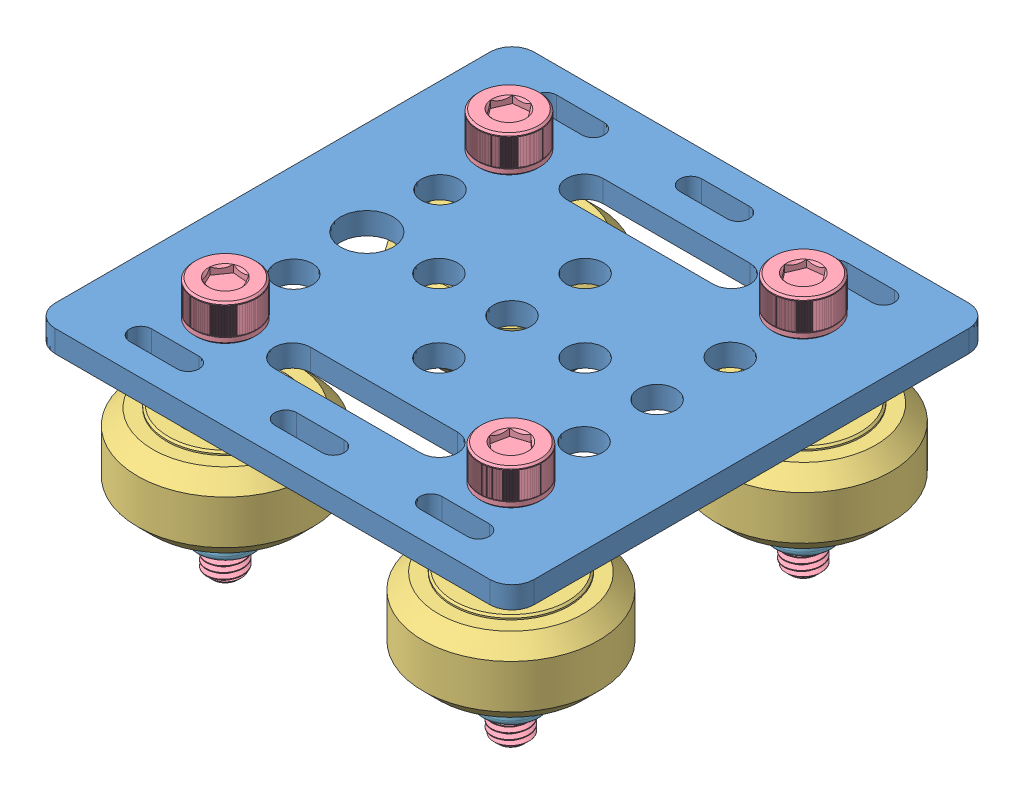
SolidWorks assembly Single Gantry Platform, configuration Default. Lengths in mm.
Overall size (72.95 35 73.59).
21 component instances, 7 part files, 40 mates.
Components (placement in the parent):
- Single Gantry Platform-1: Single Gantry Platform [Default] at (20.9715 37.2499 49.0083) size (65.5 3 65.5)
- Asymmetric_bushing-1: Asymmetric_bushing [Default] at (1.1215 35.4999 69.0083) x (0 -1 0) z (-0.085462 0 0.996341) size (8.5 10 10)
- V_slot_wheel-1: V_slot_wheel [Default] at (1.819 24.6999 69.0682) x (0 1 0) z (0.754284 0 0.656549) size (11.1 24 24)
- MT_M5_bolt-1: MT_M5_bolt [30mm] at (1.819 27.7499 69.0682) x (-0.996341 0 -0.085462) z (0 1 0) size (8.5 8.5 35)
- MT_M5_nut-1: MT_M5_nut [Default] at (1.819 16.6999 69.0682) x (0 -1 0) z (-0.615676 0 0.787999) size (5 9.24 8)
- MT_M5_Washer-1: MT_M5_Washer [Default] at (1.819 30.7499 69.0682) x (0 -1 0) z (0 0 1) size (1 8 8)
- Asymmetric_bushing-2: Asymmetric_bushing [Default] at (1.1215 35.4999 29.0083) x (0 -1 0) z (-0.985048 0 0.172282) size (8.5 10 10)
- V_slot_wheel-2: V_slot_wheel [Default] at (1.2421 24.6999 29.6979) x (0 1 0) z (0.864498 0 0.502636) size (11.1 24 24)
- MT_M5_bolt-2: MT_M5_bolt [30mm] at (1.2421 27.7499 29.6979) x (0.398878 0 -0.917004) z (0 1 0) size (8.5 8.5 35)
- MT_M5_nut-2: MT_M5_nut [Default] at (1.2421 16.6999 29.6979) x (0 -1 0) z (-0.456142 0 0.889907) size (5 9.24 8)
- MT_M5_Washer-2: MT_M5_Washer [Default] at (1.2421 30.7499 29.6979) x (0 -1 0) z (0.188455 0 0.982082) size (1 8 8)
- V_slot_wheel-4: V_slot_wheel [Default] at (40.8215 24.6999 29.0083) x (0 1 0) z (-0.83873 0 0.544547) size (11.1 24 24)
- MT_M5_bolt-4: MT_M5_bolt [30mm] at (40.8215 27.7499 29.0083) x (0.606014 0 0.795454) z (0 1 0) size (8.5 8.5 35)
- MT_M5_nut-4: MT_M5_nut [Default] at (40.8215 16.6999 29.0083) x (0 -1 0) z (-0.889907 0 -0.456142) size (5 9.24 8)
- MT_M5_Washer-4: MT_M5_Washer [Default] at (40.8215 30.7499 29.0083) x (0 -1 0) z (-0.982082 0 0.188455) size (1 8 8)
- Symmetric_bushing-1: Symmetric_bushing [Default] at (40.8215 34.2499 29.0083) x (0 -1 0) z (0 0 1) size (6 10 10)
- V_slot_wheel-6: V_slot_wheel [Default] at (40.8215 24.6999 69.0083) x (0 1 0) z (-0.721079 0 0.692853) size (11.1 24 24)
- MT_M5_bolt-6: MT_M5_bolt [30mm] at (40.8215 27.7499 69.0083) x (0.745063 0 0.666994) z (0 1 0) size (8.5 8.5 35)
- MT_M5_nut-6: MT_M5_nut [Default] at (40.8215 16.6999 69.0083) x (0 -1 0) z (-0.959924 0 -0.280262) size (5 9.24 8)
- MT_M5_Washer-6: MT_M5_Washer [Default] at (40.8215 30.7499 69.0083) x (0 -1 0) z (-0.92897 0 0.370156) size (1 8 8)
- Symmetric_bushing-2: Symmetric_bushing [Default] at (40.8215 34.2499 69.0083) x (0 -1 0) z (0.188455 0 0.982082) size (6 10 10)
Mates (geometry in assembly coordinates):
- Concentric1: concentric aligned: cylinder of Single Gantry Platform-1 through (1.1215 37.2499 69.0083) axis (0 1 0) radius 3.6; cylinder of Asymmetric_bushing-1 through (1.1215 35.4999 69.0083) axis (0 1 0) radius 3.55
- Concentric2: concentric aligned: cylinder of Asymmetric_bushing-1 through (1.819 39.7499 69.0682) axis (0 -1 0) radius 2.5; cylinder of MT_M5_bolt-1 through (1.819 10.2499 69.0682) axis (0 -1 0) radius 4.25
- Coincident2: coincident anti-aligned: plane of Single Gantry Platform-1 through (20.9715 37.2499 49.0083) normal (0 -1 0); plane of Asymmetric_bushing-1 through (6.1032 37.2499 69.4356) normal (0 1 0)
- Coincident3: coincident anti-aligned: plane of Single Gantry Platform-1 through (20.9715 40.2499 49.0083) normal (0 1 0); plane of MT_M5_bolt-1 through (1.4771 40.2499 73.0535) normal (0 -1 0)
- Coincident4: coincident anti-aligned: plane of Asymmetric_bushing-1 through (1.1215 31.2499 69.0083) normal (0 -1 0); plane of MT_M5_Washer-1 through (1.819 31.2499 69.0682) normal (0 1 0)
- Concentric3: concentric anti-aligned: cylinder of MT_M5_bolt-1 through (1.819 10.2499 69.0682) axis (0 -1 0) radius 4.25; cylinder of MT_M5_Washer-1 through (1.819 30.2499 69.0682) axis (0 1 0) radius 2.6
- Concentric4: concentric anti-aligned: cylinder of V_slot_wheel-1 through (1.819 24.1499 69.0682) axis (0 1 0) radius 2.5; cylinder of MT_M5_bolt-1 through (1.819 10.2499 69.0682) axis (0 -1 0) radius 4.25
- Coincident5: coincident anti-aligned: plane of V_slot_wheel-1 through (-1.3105 30.2499 72.6634) normal (0 1 0); plane of MT_M5_Washer-1 through (1.819 30.2499 69.0682) normal (0 -1 0)
- Concentric5: concentric aligned: cylinder of MT_M5_bolt-1 through (1.819 10.2499 69.0682) axis (0 -1 0) radius 4.25; cylinder of MT_M5_nut-1 through (1.819 19.1499 69.0682) axis (0 -1 0) radius 2.1
- Coincident6: coincident anti-aligned: plane of V_slot_wheel-1 through (0.0135 19.1499 71.1424) normal (0 -1 0); plane of MT_M5_nut-1 through (-3.1064 19.1499 75.3721) normal (0 1 0)
- Concentric6: concentric aligned: cylinder of Asymmetric_bushing-2 through (1.2421 39.7499 29.6979) axis (0 -1 0) radius 2.5; cylinder of MT_M5_bolt-2 through (1.2421 10.2499 29.6979) axis (0 -1 0) radius 4.25
- Coincident7: coincident anti-aligned: plane of Asymmetric_bushing-2 through (1.1215 31.2499 29.0083) normal (0 -1 0); plane of MT_M5_Washer-2 through (1.2421 31.2499 29.6979) normal (0 1 0)
- Concentric7: concentric anti-aligned: cylinder of MT_M5_bolt-2 through (1.2421 10.2499 29.6979) axis (0 -1 0) radius 4.25; cylinder of MT_M5_Washer-2 through (1.2421 30.2499 29.6979) axis (0 1 0) radius 2.6
- Concentric8: concentric anti-aligned: cylinder of V_slot_wheel-2 through (1.2421 24.1499 29.6979) axis (0 1 0) radius 2.5; cylinder of MT_M5_bolt-2 through (1.2421 10.2499 29.6979) axis (0 -1 0) radius 4.25
- Coincident8: coincident anti-aligned: plane of V_slot_wheel-2 through (-1.1537 30.2499 33.8185) normal (0 1 0); plane of MT_M5_Washer-2 through (1.2421 30.2499 29.6979) normal (0 -1 0)
- Concentric9: concentric aligned: cylinder of MT_M5_bolt-2 through (1.2421 10.2499 29.6979) axis (0 -1 0) radius 4.25; cylinder of MT_M5_nut-2 through (1.2421 19.1499 29.6979) axis (0 -1 0) radius 2.1
- Coincident9: coincident anti-aligned: plane of V_slot_wheel-2 through (-0.1401 19.1499 32.0752) normal (0 -1 0); plane of MT_M5_nut-2 through (-2.407 19.1499 36.8171) normal (0 1 0)
- Concentric10: concentric aligned: cylinder of Single Gantry Platform-1 through (1.1215 37.2499 29.0083) axis (0 1 0) radius 3.6; cylinder of Asymmetric_bushing-2 through (1.1215 35.4999 29.0083) axis (0 1 0) radius 3.55
- Coincident10: coincident anti-aligned: plane of Single Gantry Platform-1 through (20.9715 37.2499 49.0083) normal (0 -1 0); plane of Asymmetric_bushing-2 through (1.9829 37.2499 33.9336) normal (0 1 0)
- Coincident11: coincident anti-aligned: plane of Single Gantry Platform-1 through (20.9715 40.2499 49.0083) normal (0 1 0); plane of MT_M5_bolt-2 through (-2.4259 40.2499 28.1024) normal (0 -1 0)
- Concentric17: concentric anti-aligned: cylinder of MT_M5_bolt-4 through (40.8215 10.2499 29.0083) axis (0 -1 0) radius 4.25; cylinder of MT_M5_Washer-4 through (40.8215 30.2499 29.0083) axis (0 1 0) radius 2.6
- Concentric18: concentric anti-aligned: cylinder of V_slot_wheel-4 through (40.8215 24.1499 29.0083) axis (0 1 0) radius 2.5; cylinder of MT_M5_bolt-4 through (40.8215 10.2499 29.0083) axis (0 -1 0) radius 4.25
- Coincident18: coincident anti-aligned: plane of V_slot_wheel-4 through (38.226 30.2499 25.0105) normal (0 1 0); plane of MT_M5_Washer-4 through (40.8215 30.2499 29.0083) normal (0 -1 0)
- Concentric19: concentric aligned: cylinder of MT_M5_bolt-4 through (40.8215 10.2499 29.0083) axis (0 -1 0) radius 4.25; cylinder of MT_M5_nut-4 through (40.8215 19.1499 29.0083) axis (0 -1 0) radius 2.1
- Coincident19: coincident anti-aligned: plane of V_slot_wheel-4 through (39.324 19.1499 26.7018) normal (0 -1 0); plane of MT_M5_nut-4 through (33.7023 19.1499 25.3592) normal (0 1 0)
- Coincident21: coincident anti-aligned: plane of Single Gantry Platform-1 through (20.9715 40.2499 49.0083) normal (0 1 0); plane of MT_M5_bolt-4 through (44.0033 40.2499 26.5843) normal (0 -1 0)
- Concentric25: concentric anti-aligned: cylinder of Symmetric_bushing-1 through (40.8215 31.2499 29.0083) axis (0 1 0) radius 2.55; cylinder of MT_M5_bolt-4 through (40.8215 10.2499 29.0083) axis (0 -1 0) radius 4.25
- Coincident27: coincident anti-aligned: plane of Single Gantry Platform-1 through (20.9715 37.2499 49.0083) normal (0 -1 0); plane of Symmetric_bushing-1 through (40.8215 37.2499 29.0083) normal (0 1 0)
- Coincident28: coincident anti-aligned: plane of Symmetric_bushing-1 through (40.8215 31.2499 29.0083) normal (0 -1 0); plane of MT_M5_Washer-4 through (40.8215 31.2499 29.0083) normal (0 1 0)
- Concentric26: concentric aligned: cylinder of Single Gantry Platform-1 through (40.8215 40.2499 29.0083) axis (0 -1 0) radius 2.55; cylinder of MT_M5_bolt-4 through (40.8215 10.2499 29.0083) axis (0 -1 0) radius 4.25
- Concentric27: concentric anti-aligned: cylinder of MT_M5_bolt-6 through (40.8215 10.2499 69.0083) axis (0 -1 0) radius 4.25; cylinder of MT_M5_Washer-6 through (40.8215 30.2499 69.0083) axis (0 1 0) radius 2.6
- Concentric28: concentric anti-aligned: cylinder of V_slot_wheel-6 through (40.8215 24.1499 69.0083) axis (0 1 0) radius 2.5; cylinder of MT_M5_bolt-6 through (40.8215 10.2499 69.0083) axis (0 -1 0) radius 4.25
- Coincident29: coincident anti-aligned: plane of V_slot_wheel-6 through (37.5191 30.2499 65.5713) normal (0 1 0); plane of MT_M5_Washer-6 through (40.8215 30.2499 69.0083) normal (0 -1 0)
- Concentric29: concentric aligned: cylinder of MT_M5_bolt-6 through (40.8215 10.2499 69.0083) axis (0 -1 0) radius 4.25; cylinder of MT_M5_nut-6 through (40.8215 19.1499 69.0083) axis (0 -1 0) radius 2.1
- Coincident30: coincident anti-aligned: plane of V_slot_wheel-6 through (38.9162 19.1499 67.0254) normal (0 -1 0); plane of MT_M5_nut-6 through (33.1421 19.1499 66.7662) normal (0 1 0)
- Concentric30: concentric anti-aligned: cylinder of MT_M5_bolt-6 through (40.8215 10.2499 69.0083) axis (0 -1 0) radius 4.25; cylinder of Symmetric_bushing-2 through (40.8215 31.2499 69.0083) axis (0 1 0) radius 2.55
- Coincident31: coincident anti-aligned: plane of MT_M5_Washer-6 through (40.8215 31.2499 69.0083) normal (0 1 0); plane of Symmetric_bushing-2 through (40.8215 31.2499 69.0083) normal (0 -1 0)
- Coincident32: coincident anti-aligned: plane of Single Gantry Platform-1 through (20.9715 40.2499 49.0083) normal (0 1 0); plane of MT_M5_bolt-6 through (43.4895 40.2499 66.0281) normal (0 -1 0)
- Coincident33: coincident anti-aligned: plane of Single Gantry Platform-1 through (20.9715 37.2499 49.0083) normal (0 -1 0); plane of Symmetric_bushing-2 through (40.8215 37.2499 69.0083) normal (0 1 0)
- Concentric31: concentric aligned: cylinder of Single Gantry Platform-1 through (40.8215 40.2499 69.0083) axis (0 -1 0) radius 2.55; cylinder of MT_M5_bolt-6 through (40.8215 10.2499 69.0083) axis (0 -1 0) radius 4.25
